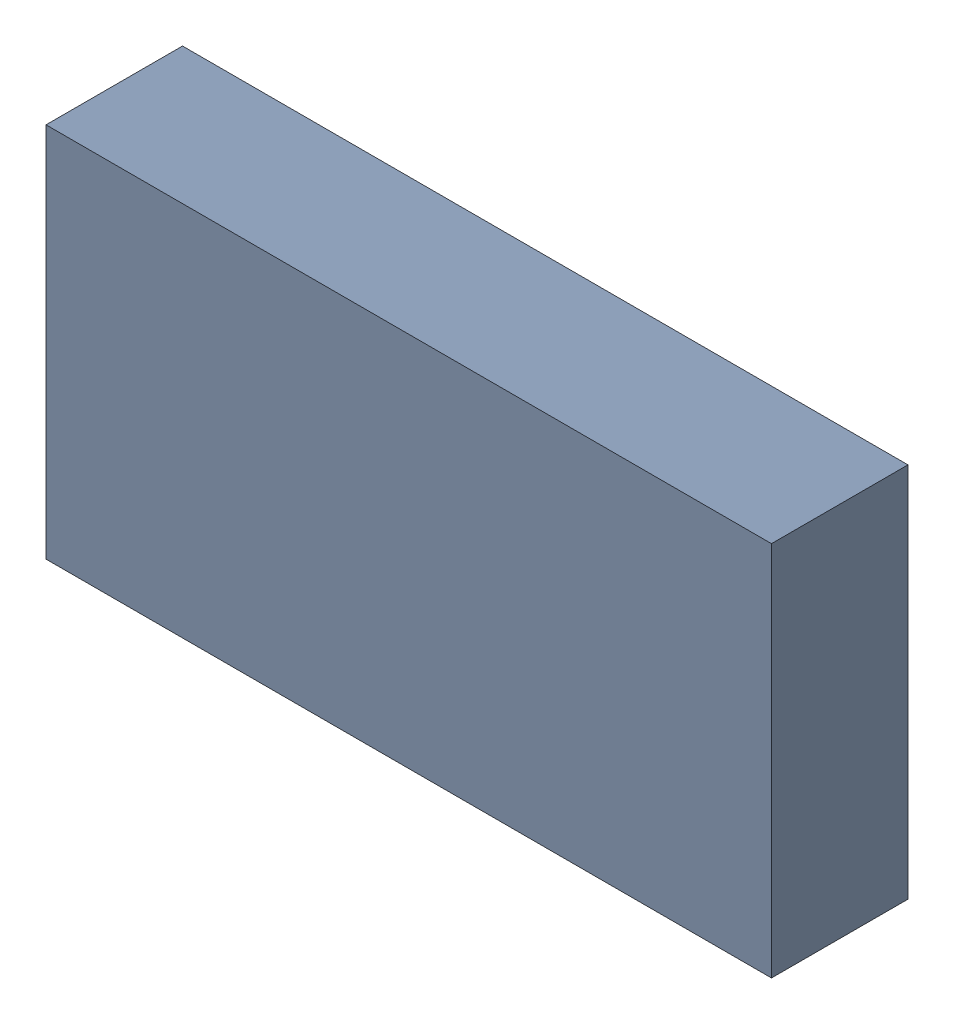
SolidWorks assembly 6327398464, configuration Default. Lengths in mm.
Overall size (1.35 0.7 0.25).
2 component instances, 1 part files, 0 mates.
Components (placement in the parent):
- 6701982208-1:  [Default] at (27.7 14.8 0) (suppressed, hidden)
- Extruded-15-1: Extruded-15 [Default] at origin size (1.35 0.7 0.25)
